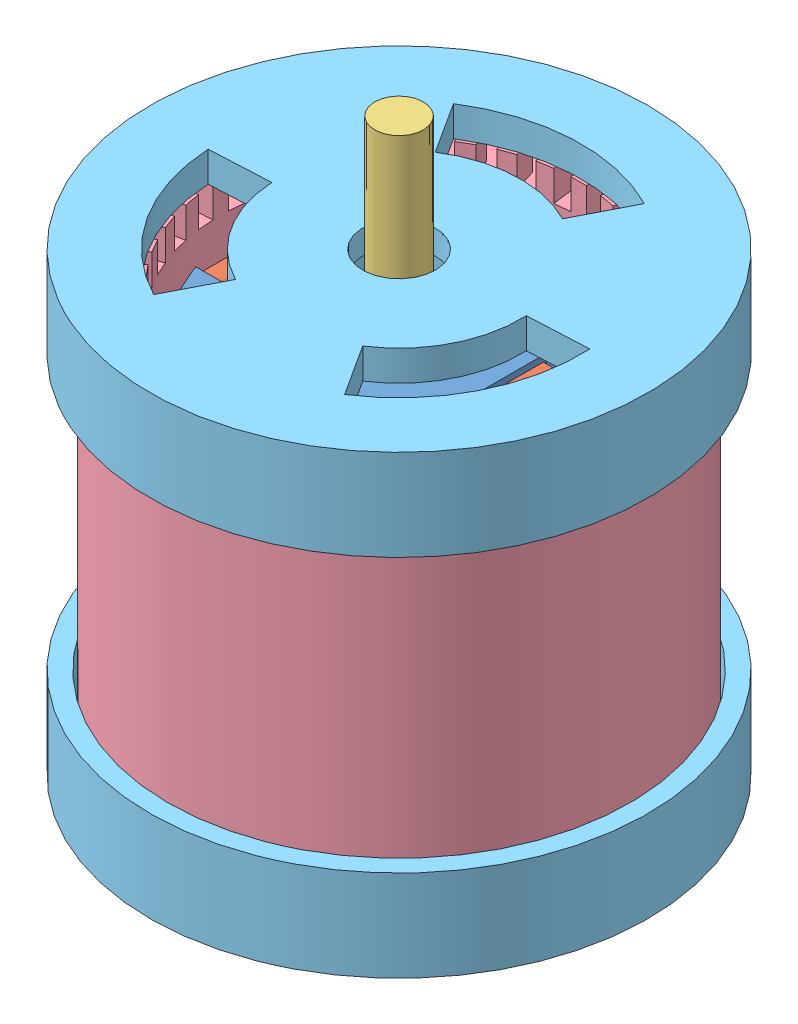
SolidWorks assembly BLDC, configuration 默认. Lengths in mm.
Overall size (110.41 100 110.41).
20 component instances, 6 part files, 10 mates.
Components (placement in the parent):
- rotor-1: rotor [默认] at (8.9629 10.2777 46.9999) size (53 100 53)
  - inner rotor-1: inner rotor [默认] at (-18.2401 -31.003 53.0001) size (53 53 53)
  - magnet x12个 rectangular new-1: magnet x12个 rectangular new [默认] at (-18.4901 -6.003 72.0001) x (1 0 0) z (0 1 0) size (16 3 50)
  - magnet x12个 rectangular new-2: magnet x12个 rectangular new [默认] at (-18.4901 -6.003 75.0001) x (1 0 0) z (0 1 0) size (16 3 50)
  - magnet x12个 rectangular new-3: magnet x12个 rectangular new [默认] at (-18.4901 -6.003 78.0001) x (1 0 0) z (0 1 0) size (16 3 50)
  - magnet x12个 rectangular new-4: magnet x12个 rectangular new [默认] at (-17.9901 -6.003 34) x (-1 0 0) z (0 1 0) size (16 3 50)
  - magnet x12个 rectangular new-5: magnet x12个 rectangular new [默认] at (-17.9901 -6.003 31.0001) x (-1 0 0) z (0 1 0) size (16 3 50)
  - magnet x12个 rectangular new-6: magnet x12个 rectangular new [默认] at (-17.9901 -6.003 28) x (-1 0 0) z (0 1 0) size (16 3 50)
  - magnet x12个 rectangular new-7: magnet x12个 rectangular new [默认] at (-34.2401 -6.003 52.7501) x (0 0 -1) z (0 1 0) size (16 3 50)
  - magnet x12个 rectangular new-8: magnet x12个 rectangular new [默认] at (-37.2401 -6.003 52.7501) x (0 0 -1) z (0 1 0) size (16 3 50)
  - magnet x12个 rectangular new-9: magnet x12个 rectangular new [默认] at (-40.2401 -6.003 52.7501) x (0 0 -1) z (0 1 0) size (16 3 50)
  - magnet x12个 rectangular new-10: magnet x12个 rectangular new [默认] at (-2.2401 -6.003 53.2501) x (0 0 1) z (0 1 0) size (16 3 50)
  - magnet x12个 rectangular new-11: magnet x12个 rectangular new [默认] at (0.7599 -6.003 53.2501) x (0 0 1) z (0 1 0) size (16 3 50)
  - magnet x12个 rectangular new-12: magnet x12个 rectangular new [默认] at (3.7599 -6.003 53.2501) x (0 0 1) z (0 1 0) size (16 3 50)
  - 8mm shaft-1: 8mm shaft [默认] at (-18.2401 -50.003 53.0001) x (0.206718 0 -0.978401) z (0.978401 0 0.206718) size (8 100 8)
- stator ring-1: stator ring [默认] at (-9.2772 -23.7253 100) x (0.999185 0 -0.040368) z (0.040368 0 0.999185) size (75 65 75)
- stator cap-1: stator cap [默认] at (-9.2772 -18.7253 100) x (-0.910949 0 0.41252) z (0.41252 0 0.910949) size (82 15 82)
- 8mm bearing-1: 8mm bearing [默认] at (-9.2772 -29.7253 100) size (19 6 19)
- stator cap-2: stator cap [默认] at (-9.2772 26.2747 100) x (0.889452 0 0.457028) z (-0.457028 0 0.889452) size (82 15 82)
- 8mm bearing-2: 8mm bearing [默认] at (-9.2772 31.2747 100) size (19 6 19) (hidden)
Mates (geometry in assembly coordinates):
- Concentric1: concentric aligned: cylinder of rotor-1/8mm shaft-1 through (-9.2772 60.2747 100) axis (0 -1 0) radius 4; cylinder of stator ring-1 through (-9.2772 31.2747 100) axis (0 -1 0) radius 37.5
- Distance1: distance = 2 mm aligned: plane of rotor-1/magnet x12个 rectangular new-9 through (-34.2772 29.2747 91.75) normal (0 1 0); plane of stator ring-1 through (-9.2772 31.2747 100) normal (0 1 0)
- Concentric2: concentric anti-aligned: cylinder of stator ring-1 through (-9.2772 31.2747 100) axis (0 -1 0) radius 37.5; cylinder of stator cap-1 through (-9.2772 -28.7253 100) axis (0 1 0) radius 38
- Coincident2: coincident anti-aligned: plane of stator ring-1 through (-9.2772 -28.7253 100) normal (0 -1 0); plane of stator cap-1 through (-9.2772 -28.7253 100) normal (0 1 0)
- Concentric3: concentric anti-aligned: cylinder of stator cap-1 through (-9.2772 -29.7253 100) axis (0 1 0) radius 10; cylinder of 8mm bearing-1 through (-9.2772 -23.7253 100) axis (0 -1 0) radius 9.5
- Coincident3: coincident anti-aligned: plane of stator cap-1 through (-9.2772 -29.7253 100) normal (0 1 0); plane of 8mm bearing-1 through (-9.2772 -29.7253 100) normal (0 -1 0)
- Concentric4: concentric aligned: cylinder of stator ring-1 through (-9.2772 31.2747 100) axis (0 -1 0) radius 37.5; cylinder of stator cap-2 through (-9.2772 36.2747 100) axis (0 -1 0) radius 38
- Coincident4: coincident anti-aligned: plane of stator ring-1 through (-9.2772 36.2747 100) normal (0 1 0); plane of stator cap-2 through (-9.2772 36.2747 100) normal (0 -1 0)
- Coincident5: coincident anti-aligned: plane of stator cap-2 through (-9.2772 37.2747 100) normal (0 -1 0); plane of 8mm bearing-2 through (-9.2772 37.2747 100) normal (0 1 0)
- Concentric5: concentric aligned: cylinder of rotor-1/8mm shaft-1 through (-9.2772 60.2747 100) axis (0 -1 0) radius 4; cylinder of 8mm bearing-2 through (-9.2772 37.2747 100) axis (0 -1 0) radius 4
